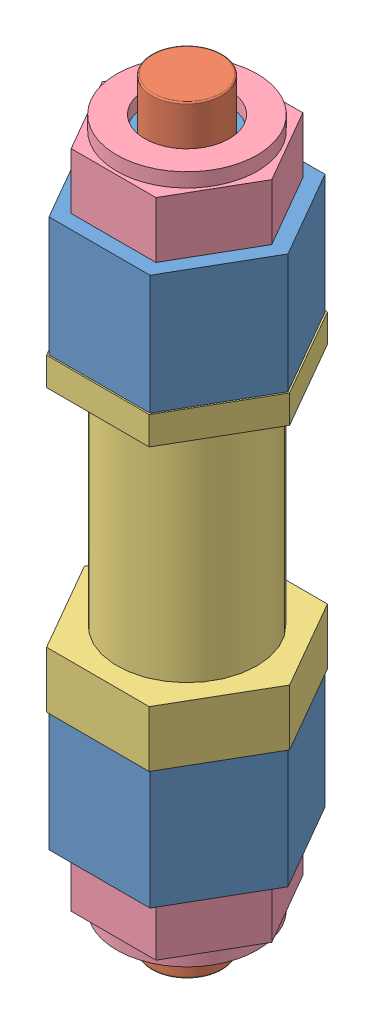
SolidWorks assembly ass-final, configuration Default. Lengths in mm.
Overall size (29.28 111.58 25.37).
7 component instances, 4 part files, 14 mates.
Components (placement in the parent):
- BlueScrew-1: BlueScrew [Default] at origin size (28.75 26.78 24.9)
- metal-cyc-1: metal-cyc [Default] at (0 0.5 0) x (-1 0 0) z (0 -1 0) size (10 10 38.86)
- double-s-teflon-1: double-s-teflon [Default] at (0 3 0) x (0.999999 0 0.001387) z (0 1 0) size (29.25 25.33 72)
- metal-cyc-2: metal-cyc [Default] at (0 77.5 0) x (0.997727 0 0.067388) z (0 1 0) size (10 10 38.86)
- cap-pressure-1: cap-pressure [Default] at (0 -8 0) x (-1 0 0) z (0 -1 0) size (24.13 20.9 10.28)
- BlueScrew-4: BlueScrew [Default] at (0 78 0) x (1 0 0) z (0 0 -1) size (28.75 26.78 24.9)
- cap-pressure-2: cap-pressure [Default] at (0 86 0) x (1 0 0) z (0 1 0) size (24.13 20.9 10.28)
Mates (geometry in assembly coordinates):
- Concentric1: concentric: circle of BlueScrew-1; circle of metal-cyc-1
- Coincident13: coincident anti-aligned: plane of BlueScrew-1 through (0 3 0) normal (0 1 0); plane of double-s-teflon-1 through (0 3 0) normal (0 -1 0)
- Concentric2: concentric aligned: circle of BlueScrew-1; circle of double-s-teflon-1
- Distance3: distance = 7.98 mm anti-aligned: plane of ? through (0 24.98 0) normal (0 -1 0); plane of BlueScrew-1 through (0 17 0) normal (0 1 0)
- Concentric3: concentric anti-aligned: circle of double-s-teflon-1; circle of ?
- Distance4: distance = 45 mm aligned: plane of metal-cyc-2 through (0 62 0) normal (0 -1 0); plane of double-s-teflon-1 through (0 17 0) normal (0 -1 0)
- InPlace1: in place: plane of BlueScrew-1 through (0 -8 0) normal (0 -1 0); plane of cap-pressure-1 through (0 -8 0) normal (0 -1 0); moOrthogonalPlaneRef_w of BlueScrew-1 through (0 -8 0) normal (0 -1 0); unknown of cap-pressure-1; plane of BlueScrew-1 through (0 -8 0) normal (0 -1 0); line of cap-pressure-1 through (-55 0 -8) axis (0 -1 0); plane of BlueScrew-1 through (0 -8 0) normal (0 -1 0); unknown of cap-pressure-1
- Coincident14: coincident aligned: plane of BlueScrew-1; plane of cap-pressure-1
- Coincident15: coincident aligned: moOrthogonalPlaneRef_w of BlueScrew-1 through (0 -8 0) normal (0 0 -1); plane of cap-pressure-1
- Coincident16: coincident anti-aligned: moOrthogonalPlaneRef_w of BlueScrew-1 through (0 -8 0) normal (1 0 0); plane of cap-pressure-1
- Coincident17: coincident anti-aligned: plane of double-s-teflon-1 through (0 61 0) normal (0 1 0); plane of BlueScrew-4 through (0 61 0) normal (0 -1 0)
- Concentric5: concentric anti-aligned: circle of metal-cyc-2; circle of BlueScrew-4
- Coincident18: coincident anti-aligned: plane of BlueScrew-4 through (0 78 0) normal (0 1 0); plane of cap-pressure-2 through (0 78 0) normal (0 -1 0)
- Concentric6: concentric anti-aligned: circle of BlueScrew-4; circle of cap-pressure-2
